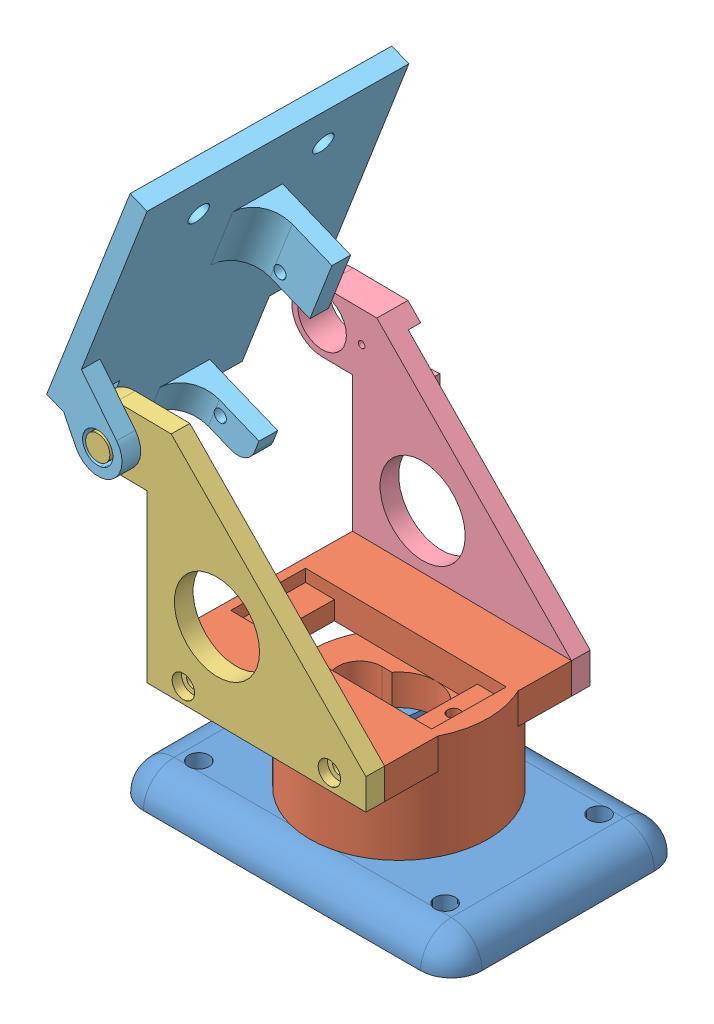
SolidWorks assembly pan_tilt, configuration 默认. Lengths in mm.
Overall size (68.59 87.43 42.64).
5 component instances, 5 part files, 10 mates.
Components (placement in the parent):
- base-1: base [默认] at (-4.9867 -5.0166 55) size (55 11 38)
- rotate-1: rotate [默认] at (-9.9863 16.9834 54.9403) x (0.999929 0 0.011939) z (0.011939 0 -0.999929) size (37.5 17 30)
- left-1: left [默认] at (-10.1654 11.9834 69.9392) x (0.999929 0 0.011939) z (-0.011939 0 0.999929) size (46 37 6)
- right-1: right [默认] at (-9.7714 11.9834 36.9416) x (0.999929 0 0.011939) z (-0.011939 0 0.999929) size (46 37 5)
- head-1: head [默认] at (-33.9496 58.027 54.6542) x (-0.011939 0 0.999929) z (-0.931636 0.363222 -0.011123) size (42 50 15)
Mates (geometry in assembly coordinates):
- 同心1: concentric aligned: cylinder of base-1 through (-4.9867 5.9834 55) axis (0 -1 0) radius 10.9; cylinder of rotate-1 through (-4.9867 6.9834 55) axis (0 -1 0) radius 12
- 重合1: coincident anti-aligned: plane of base-1 through (-4.9867 -0.0166 55) normal (0 1 0); plane of rotate-1 through (-4.9867 -0.0166 55) normal (0 -1 0)
- 同心2: concentric aligned: cylinder of rotate-1 through (1.8934 14.4834 65.0829) axis (-0.011939 0 0.999929) radius 1; cylinder of left-1 through (1.8337 14.4834 70.0825) axis (-0.011939 0 0.999929) radius 1
- 同心3: concentric aligned: cylinder of rotate-1 through (-22.1049 14.4834 64.7963) axis (-0.011939 0 0.999929) radius 1; cylinder of left-1 through (-22.1646 14.4834 69.796) axis (-0.011939 0 0.999929) radius 1
- 重合2: coincident anti-aligned: plane of rotate-1 through (-28.1641 11.9834 69.7243) normal (-0.011939 0 0.999929); plane of left-1 through (-10.1654 11.9834 69.9392) normal (0.011939 0 -0.999929)
- 同心4: concentric anti-aligned: cylinder of rotate-1 through (2.1322 14.4834 45.0843) axis (0.011939 0 -0.999929) radius 1; cylinder of right-1 through (2.2277 14.4834 37.0849) axis (-0.011939 0 0.999929) radius 1
- 同心5: concentric anti-aligned: cylinder of rotate-1 through (-21.8661 14.4834 44.7978) axis (0.011939 0 -0.999929) radius 1; cylinder of right-1 through (-21.7706 14.4834 36.7983) axis (-0.011939 0 0.999929) radius 1
- 重合3: coincident anti-aligned: plane of rotate-1 through (-27.806 11.9834 39.7265) normal (0.011939 0 -0.999929); plane of right-1 through (-9.8072 11.9834 39.9414) normal (-0.011939 0 0.999929)
- 同心6: concentric anti-aligned: cylinder of left-1 through (-33.2354 43.9834 75.6642) axis (0.011939 0 -0.999929) radius 2; cylinder of head-1 through (-33.1996 43.9834 72.6644) axis (-0.011939 0 0.999929) radius 2.5
- 重合4: coincident anti-aligned: plane of left-1 through (-10.2012 11.9834 72.939) normal (-0.011939 0 0.999929); plane of head-1 through (-33.1996 43.9834 72.6644) normal (0.011939 0 -0.999929)
